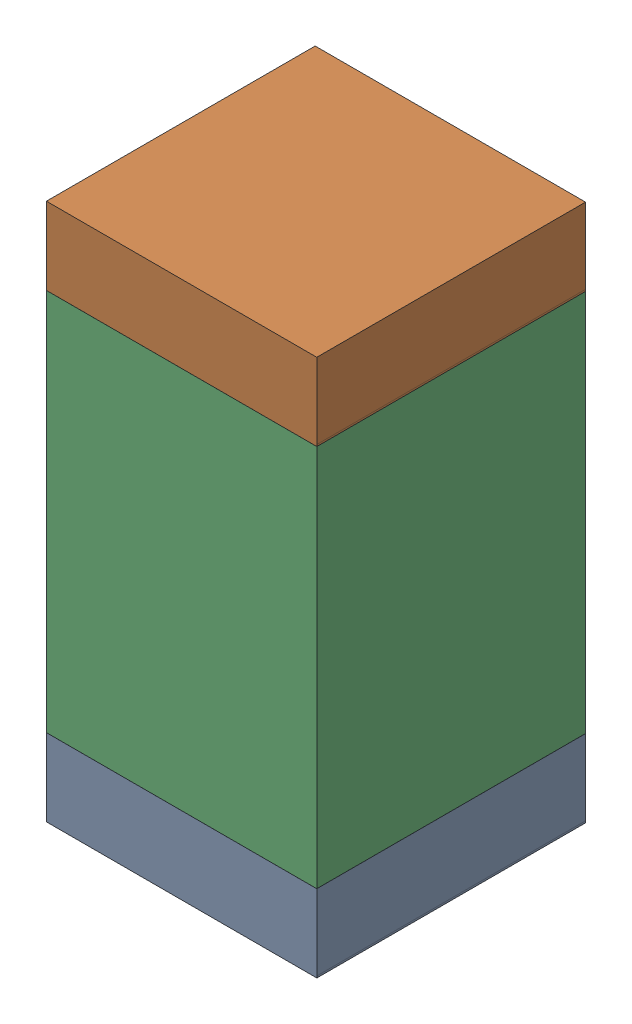
SolidWorks assembly C7, configuration 默认. Lengths in mm.
Overall size (0.81 1.6 0.8).
6 component instances, 2 part files, 0 mates.
Components (placement in the parent):
- 6641443168-1: 6641443168 [默认] at (12.3314 3.3249 -2.6339) size (0.8 0.23 0.8)
  - Extruded-24-1: Extruded-24 [默认] at origin size (0.8 0.23 0.8)
- 6641443168-2: 6641443168 [默认] at (12.3314 4.6949 -2.6339) size (0.8 0.23 0.8)
  - Extruded-24-1: Extruded-24 [默认] at origin size (0.8 0.23 0.8)
- 6641442768-1: 6641442768 [默认] at (12.3313 4.0099 -2.6339) size (0.8 1.14 0.8)
  - Extruded-25-1: Extruded-25 [默认] at origin size (0.8 1.14 0.8)
